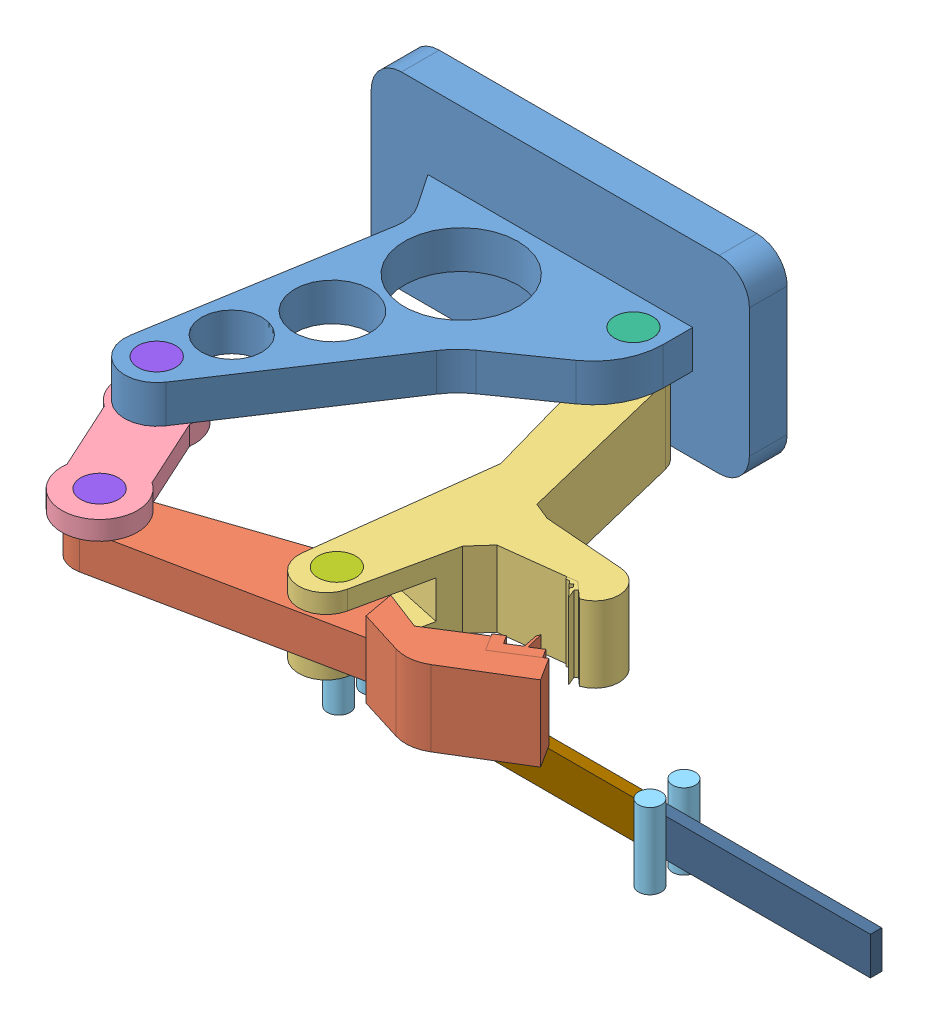
SolidWorks assembly 飞剪, configuration 默认. Lengths in mm.
Overall size (211.83 70.63 164.64).
12 component instances, 10 part files, 24 mates.
Components (placement in the parent):
- 底座-1: 底座 [默认] at (-2.1035 17.0758 -47.9901) size (100 50 95.98)
- 上飞剪-1: 上飞剪 [默认] at (30.6731 7.0758 53.8737) x (0.673636 0 -0.739064) z (0 -1 0) size (88.25 72.57 20)
- 下飞剪-1: 下飞剪 [默认] at (30.6731 12.0758 53.8737) x (0.992674 0 -0.120822) z (0 -1 0) size (55.35 100.5 20)
- 曲柄-1: 曲柄 [默认] at (-18.6048 12.0758 67.317) x (0.909234 0 -0.416286) z (0 -1 0) size (20.03 50.57 5)
- 卡扣-1: 卡扣 [默认] at (22.1447 -8.5513 44.8503) x (1 0 0) z (0 -1 0) size (6 15 20)
- 卡扣-2: 卡扣 [默认] at (104.4285 -8.5513 44.8503) x (1 0 0) z (0 -1 0) size (6 15 20)
- 销1-1: 销1 [默认] at (25.0237 -7.9242 -30.2037) x (1 0 0) z (0 1 0) size (10 10 30)
- 销2-1: 销2 [默认] at (30.6731 -7.9242 53.8737) x (1 0 0) z (0 1 0) size (10 10 20)
- 销-1: 销 [默认] at (-18.6048 -2.9242 67.317) x (1 0 0) z (0 1 0) size (10 10 15)
- 销-2: 销 [默认] at (-31.3033 7.0758 39.507) x (1 0 0) z (0 1 0) size (10 10 15)
- 零件1-1: 零件1 [默认] at (59.6897 -13.5513 41.8503) x (1 0 0) z (0 -1 0) size (40 3 10)
- 零件2-1: 零件2 [默认] at (99.726 -13.5513 41.8503) x (1 0 0) z (0 -1 0) size (60 3 10)
Mates (geometry in assembly coordinates):
- 同心1: concentric: cylinder of 底座-1 through (-31.3033 22.0758 39.507) axis (0 -1 0) radius 5; cylinder of 曲柄-1 through (-31.3033 7.0758 39.507) axis (0 1 0) radius 5
- 重合1: coincident: plane of 底座-1 through (14.4008 12.0758 -30.2037) normal (0 -1 0); plane of 曲柄-1 through (-20.2965 12.0758 10.9851) normal (0 1 0)
- 同心2: concentric: cylinder of ? through (-20.2965 -2.9242 10.9851) axis (0 1 0) radius 5; cylinder of ? through (-20.2965 7.0758 10.9851) axis (0 1 0) radius 5
- 重合2: coincident: plane of ? through (-20.2965 7.0758 10.9851) normal (0 1 0); plane of ? through (-20.2965 7.0758 10.9851) normal (0 -1 0)
- 同心3: concentric: cylinder of ? through (9.3355 -2.9242 52.59) axis (0 1 0) radius 5; cylinder of ? through (9.3355 -7.9242 52.59) axis (0 1 0) radius 5
- 重合3: coincident: plane of ? through (-20.2965 7.0758 10.9851) normal (0 1 0); plane of ? through (8.2071 7.0758 54.5867) normal (0 -1 0)
- 同心4: concentric: cylinder of 底座-1 through (25.0237 22.0758 -30.2037) axis (0 -1 0) radius 5; cylinder of ? through (25.0237 -7.9242 -30.2037) axis (0 1 0) radius 5
- 重合4: coincident: plane of 底座-1 through (14.4008 12.0758 -30.2037) normal (0 -1 0); plane of ? through (8.2071 12.0758 54.5867) normal (0 1 0)
- 同心5: concentric: cylinder of 曲柄-1 through (-31.3033 7.0758 39.507) axis (0 1 0) radius 5; cylinder of 销-2 through (-31.3033 22.0758 39.507) axis (0 -1 0) radius 5
- 重合5: coincident: plane of 曲柄-1 through (-20.2965 7.0758 10.9851) normal (0 -1 0); plane of 销-2 through (-31.3033 7.0758 39.507) normal (0 -1 0)
- 同心6: concentric: cylinder of ? through (-20.2965 -2.9242 10.9851) axis (0 1 0) radius 5; cylinder of ? through (-20.2965 12.0758 10.9851) axis (0 -1 0) radius 5
- 重合6: coincident: plane of ? through (-20.2965 -2.9242 10.9851) normal (0 -1 0); plane of ? through (-20.2965 -2.9242 10.9851) normal (0 -1 0)
- 同心7: concentric: cylinder of ? through (9.3355 -7.9242 52.59) axis (0 1 0) radius 5; cylinder of 销2-1 through (9.3355 12.0758 52.59) axis (0 -1 0) radius 5
- 重合7: coincident: plane of ? through (8.2071 -7.9242 54.5867) normal (0 -1 0); plane of ? through (9.3355 -7.9242 52.59) normal (0 -1 0)
- 同心8: concentric: cylinder of ? through (25.0237 -7.9242 -30.2037) axis (0 1 0) radius 5; cylinder of 销1-1 through (25.0237 22.0758 -30.2037) axis (0 -1 0) radius 5
- 重合8: coincident: plane of ? through (8.2071 -7.9242 54.5867) normal (0 -1 0); plane of 销1-1 through (25.0237 -7.9242 -30.2037) normal (0 -1 0)
- 重合11: coincident aligned: plane of 卡扣-1 through (22.1447 -28.5513 44.8503) normal (0 -1 0); plane of 卡扣-2 through (104.4285 -28.5513 44.8503) normal (0 -1 0)
- 重合12: coincident: plane of 零件1-1 through (-11.5913 -23.5513 38.8503) normal (0 0 -1); plane of 零件2-1 through (48.4786 -23.5513 38.8503) normal (0 0 -1)
- 重合13: coincident: plane of ? through (-11.5913 -23.5513 38.8503) normal (0 -1 0); plane of ? through (48.4786 -23.5513 38.8503) normal (0 -1 0)
- 平行2: parallel: plane of 底座-1 through (39.8965 0.0758 -37.9901) normal (0 0 1); plane of ? through (48.4786 -23.5513 38.8503) normal (0 0 -1)
- 平行3: parallel: plane of 底座-1 through (-44.1035 -7.9242 -37.9901) normal (0 -1 0); plane of ? through (48.4786 -23.5513 38.8503) normal (0 -1 0)
- 相切1: tangent: cylinder of 卡扣-2 through (104.4285 -28.5513 35.8503) axis (0 1 0) radius 3; plane of ? through (48.4786 -23.5513 38.8503) normal (0 0 -1)
- 相切2: tangent: cylinder of 卡扣-1 through (22.1447 -28.5513 35.8503) axis (0 1 0) radius 3; plane of ? through (-11.5913 -23.5513 38.8503) normal (0 0 -1)
- 距离1: distance = 5 mm: plane of 零件2-1 through (99.726 -23.5513 38.8503) normal (0 -1 0); plane of 卡扣-2 through (104.4285 -28.5513 44.8503) normal (0 -1 0)
